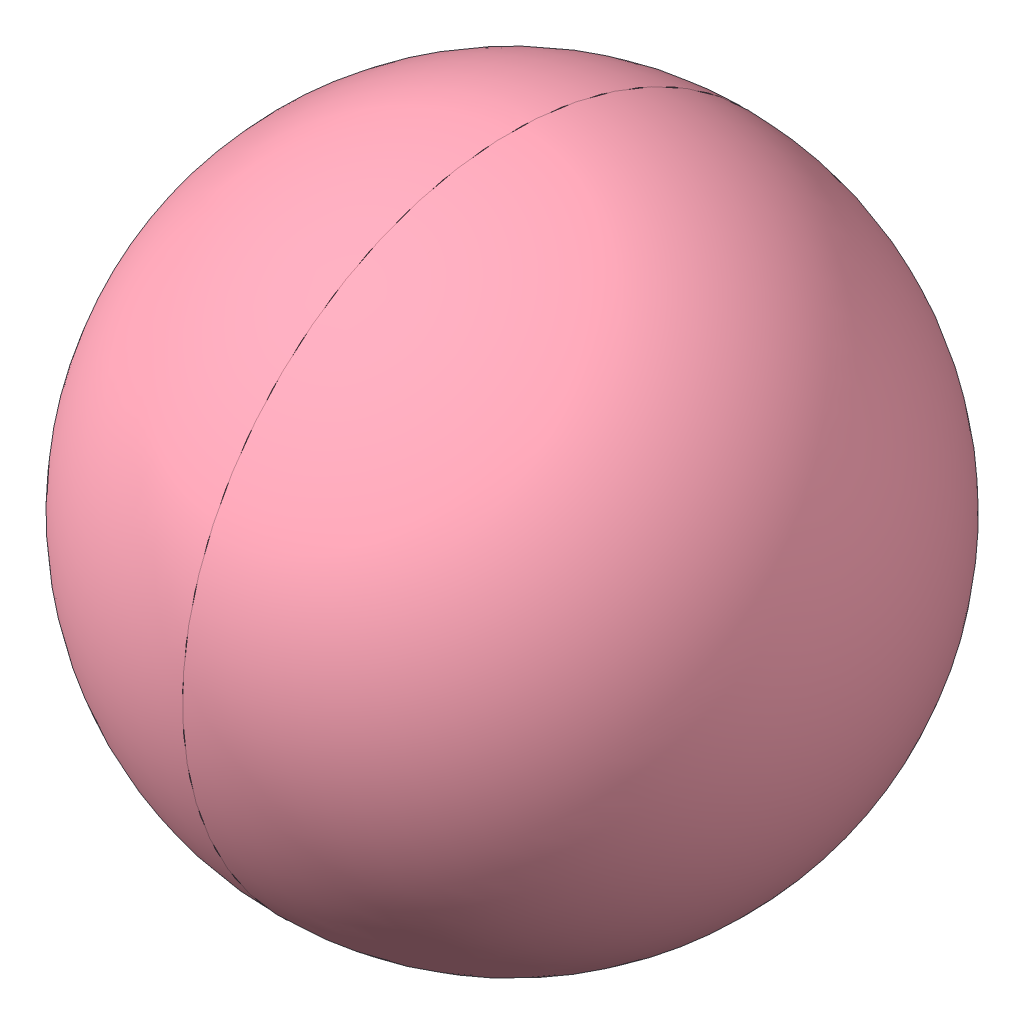
SolidWorks assembly MainRolers, configuration Default. Lengths in mm.
Overall size (100 140.81 140.81).
9 component instances, 5 part files, 19 mates.
Components (placement in the parent):
- Base-1: Base [Default] at (37.3353 -161.0107 -76.7882) x (1 0 0) z (0 0.142722 0.989763) size (50 4 74.16)
- Motor Mount-1: Motor Mount [Default] at (15.3353 -157.0516 -77.3591) x (0 -0.142722 -0.989763) z (1 0 0) size (15.67 16 4)
- Motor Mount-2: Motor Mount [Default] at (55.3353 -157.0516 -77.3591) x (0 -0.142722 -0.989763) z (1 0 0) size (15.67 16 4)
- Wheel-1: Wheel [Default] at (67.3353 -150.1233 -78.3582) x (0 0.99478 -0.102045) z (0 -0.102045 -0.99478) size (40.79 4.01 40.79)
- Wheel-2: Wheel [Default] at (7.3353 -150.1233 -78.3582) x (0 -0.999972 -0.007423) z (0 0.007423 -0.999972) size (40.79 4.01 40.79)
- Outer Sphere-1: Outer Sphere [Default] at (37.3353 -96.5296 -48.2985) x (0 0.769581 0.638549) z (-1 0 0) size (100 100 50)
- Outer Sphere-2: Outer Sphere [Default] at (37.3353 -174.7834 -110.5238) x (0 -0.795497 -0.605958) z (1 0 0) size (100 100 50)
- Roller-1: Roller [Default] at (23.3353 -163.1668 -110.0284) x (1 0 0) z (0 -0.697181 0.716895) size (28 12 12)
- Roller-2: Roller [Default] at (23.3353 -155.1431 -43.1578) x (1 0 0) z (0 -0.263941 -0.964539) size (28 12 12)
Mates (geometry in assembly coordinates):
- Coincident1: coincident anti-aligned: plane of Base-1 through (19.3353 -157.0516 -77.3591) normal (-1 0 0); plane of Motor Mount-1 through (19.3353 -157.0516 -77.3591) normal (1 0 0)
- Coincident2: coincident aligned: plane of Base-1 through (37.3353 -161.0107 -76.7882) normal (0 -0.989763 0.142722); plane of Motor Mount-1 through (19.3353 -161.0107 -76.7882) normal (0 -0.989763 0.142722)
- Coincident3: coincident anti-aligned: plane of Base-1 through (37.3353 -156.7662 -75.3796) normal (0 -0.142722 -0.989763); plane of Motor Mount-1 through (19.3353 -156.7662 -75.3796) normal (0 0.142722 0.989763)
- Coincident4: coincident anti-aligned: plane of Base-1 through (59.3353 -157.0516 -77.3591) normal (-1 0 0); plane of Motor Mount-2 through (59.3353 -157.0516 -77.3591) normal (1 0 0)
- Coincident5: coincident anti-aligned: plane of Base-1 through (37.3353 -156.7662 -75.3796) normal (0 -0.142722 -0.989763); plane of Motor Mount-2 through (59.3353 -156.7662 -75.3796) normal (0 0.142722 0.989763)
- Coincident6: coincident aligned: plane of Base-1 through (37.3353 -161.0107 -76.7882) normal (0 -0.989763 0.142722); plane of Motor Mount-2 through (59.3353 -161.0107 -76.7882) normal (0 -0.989763 0.142722)
- Concentric1: concentric aligned: circle of Motor Mount-2; circle of Wheel-1
- Concentric2: concentric anti-aligned: circle of Motor Mount-1; circle of Wheel-2
- Distance1: distance = 68 mm anti-aligned: plane of Wheel-1 through (71.3353 -150.1233 -78.3582) normal (1 0 0); plane of Wheel-2 through (3.3353 -150.1233 -78.3582) normal (-1 0 0)
- Width1: width anti-aligned: plane of Wheel-2 through (7.3353 -150.1233 -78.3582) normal (1 0 0); plane of Wheel-1 through (67.3353 -150.1233 -78.3582) normal (-1 0 0); plane of Base-1 through (12.3353 -157.0516 -77.3591) normal (-1 0 0); plane of Base-1 through (62.3353 -157.0516 -77.3591) normal (1 0 0)
- Coincident7: coincident anti-aligned: plane of Outer Sphere-1 through (37.3353 -135.0086 -80.2259) normal (1 0 0)
- Coincident8: coincident anti-aligned: plane of Outer Sphere-1 through (37.3353 -135.0086 -80.2259) normal (1 0 0); plane of Outer Sphere-2 through (37.3353 -135.0086 -80.2259) normal (-1 0 0)
- Concentric4: concentric anti-aligned: circle of Outer Sphere-1; circle of Outer Sphere-2
- Tangent1: tangent: sphere of Wheel-1; unknown of ?
- Concentric6: concentric aligned: circle of Roller-1
- Coincident17: coincident aligned: circle of Roller-2
- Coincident18: coincident aligned: circle of Roller-1
- Concentric9: concentric aligned: circle of Roller-2
- Tangent3: tangent aligned: edge_curve of Outer Sphere-2
